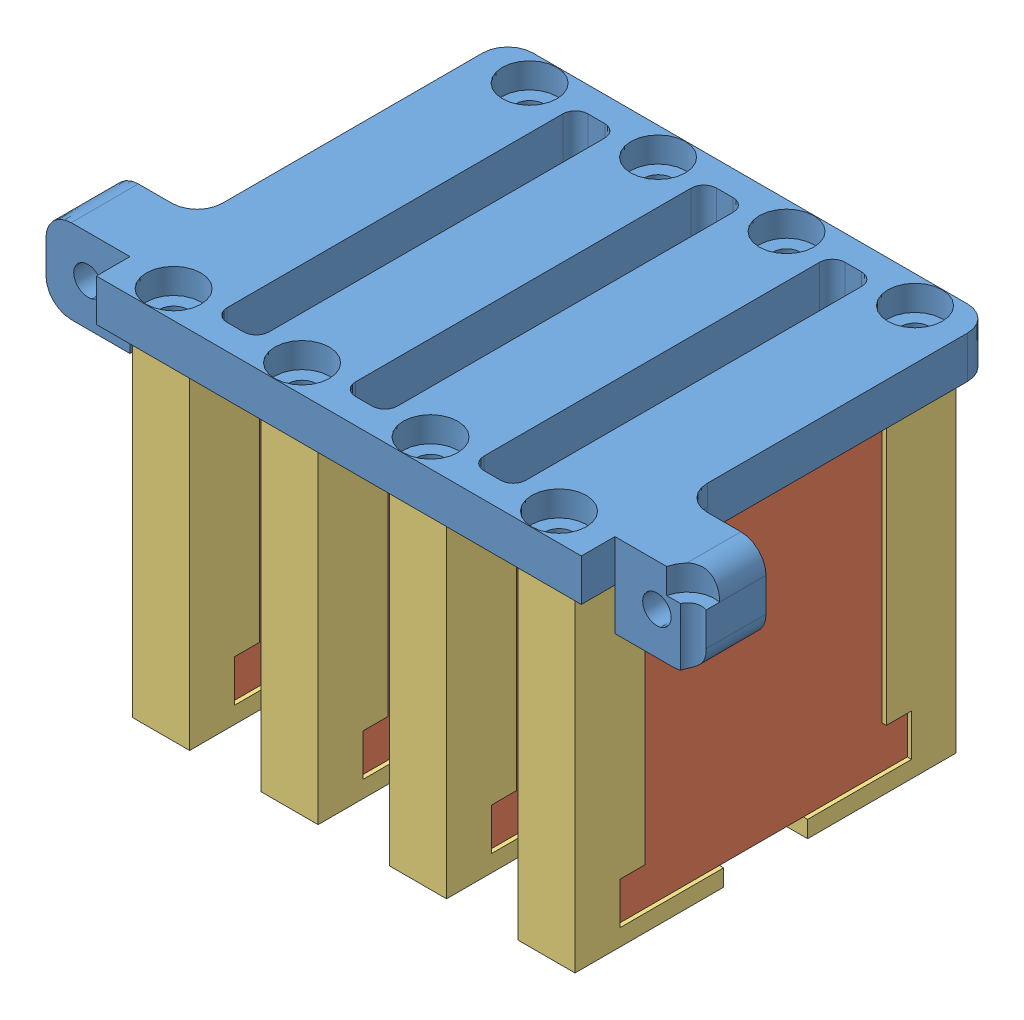
SolidWorks assembly VerticalBraceMagnets, configuration Default. Lengths in mm.
Overall size (77.76 45.19 49).
13 component instances, 3 part files, 0 mates.
Components (placement in the parent):
- MagnetBracket_draft4_20160427-1: MagnetBracket_draft4_20160427 [Default] at (-252.0457 -3.1326 136.3687) size (77.76 10 49)
- BraceMagVertSolid_draft6_20160427-2: BraceMagVertSolid_draft6_20160427 [Default] at (-186.916 -115.49 293.8662) x (0 0 1) z (0 1 0) size (45.4 6.82 42.19)
  - MagnetActual_draf6_20160424-1: MagnetActual_draf6_20160424 [Default] at (-195.3725 -16.2397 114.3575) size (34.75 5.82 40.19)
  - VertMagBraceSolid_draft3_20160427-1: VertMagBraceSolid_draft3_20160427 [Default] at (-155.2965 -9.9197 112.0675) x (0 0 -1) z (0 1 0) size (39.9 45.4 6.82)
- BraceMagVertSolid_draft6_20160427-3: BraceMagVertSolid_draft6_20160427 [Default] at (-202.216 -115.49 293.8662) x (0 0 1) z (0 1 0) size (45.4 6.82 42.19)
  - MagnetActual_draf6_20160424-1: MagnetActual_draf6_20160424 [Default] at (-195.3725 -16.2397 114.3575) size (34.75 5.82 40.19)
  - VertMagBraceSolid_draft3_20160427-1: VertMagBraceSolid_draft3_20160427 [Default] at (-155.2965 -9.9197 112.0675) x (0 0 -1) z (0 1 0) size (39.9 45.4 6.82)
- BraceMagVertSolid_draft6_20160427-4: BraceMagVertSolid_draft6_20160427 [Default] at (-217.516 -115.49 293.8662) x (0 0 1) z (0 1 0) size (45.4 6.82 42.19)
  - MagnetActual_draf6_20160424-1: MagnetActual_draf6_20160424 [Default] at (-195.3725 -16.2397 114.3575) size (34.75 5.82 40.19)
  - VertMagBraceSolid_draft3_20160427-1: VertMagBraceSolid_draft3_20160427 [Default] at (-155.2965 -9.9197 112.0675) x (0 0 -1) z (0 1 0) size (39.9 45.4 6.82)
- BraceMagVertSolid_draft6_20160427-5: BraceMagVertSolid_draft6_20160427 [Default] at (-232.816 -115.49 293.8662) x (0 0 1) z (0 1 0) size (45.4 6.82 42.19)
  - MagnetActual_draf6_20160424-1: MagnetActual_draf6_20160424 [Default] at (-195.3725 -16.2397 114.3575) size (34.75 5.82 40.19)
  - VertMagBraceSolid_draft3_20160427-1: VertMagBraceSolid_draft3_20160427 [Default] at (-155.2965 -9.9197 112.0675) x (0 0 -1) z (0 1 0) size (39.9 45.4 6.82)
